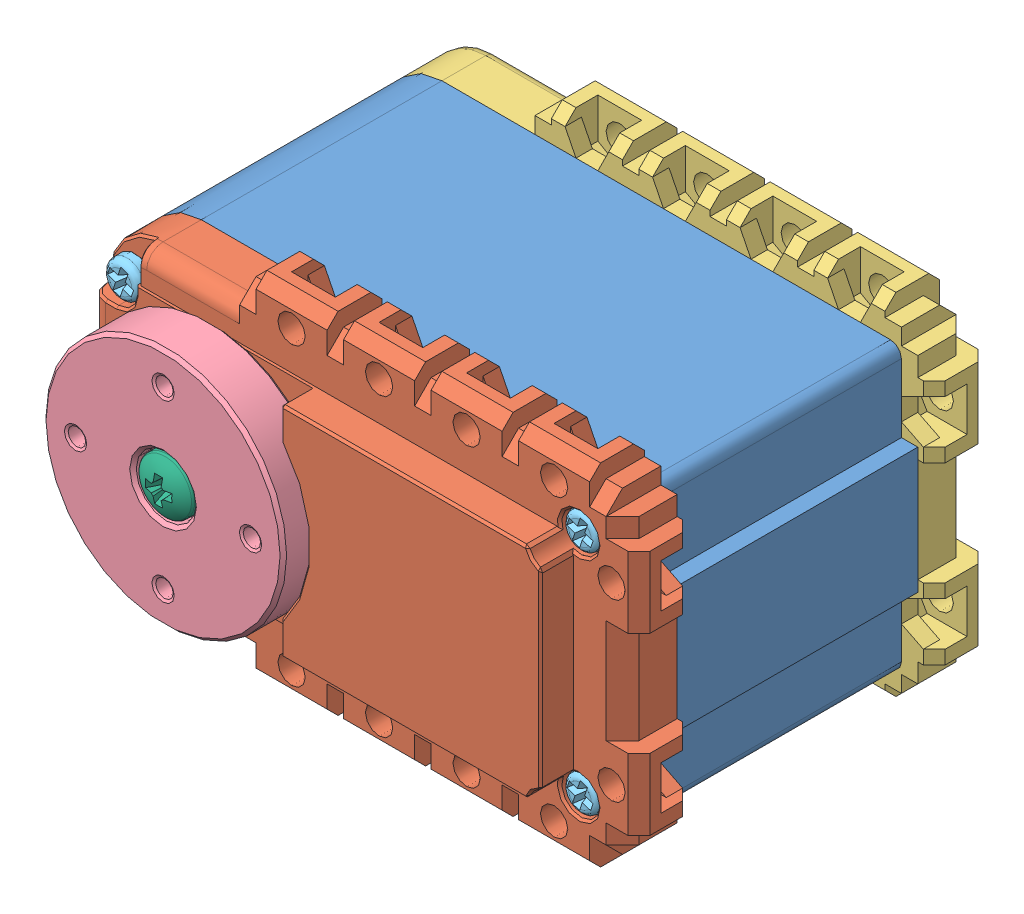
SolidWorks assembly AX-12A, configuration Default. Lengths in mm.
Overall size (50 32 40.55).
9 component instances, 6 part files, 19 mates.
Components (placement in the parent):
- AX-12A-01-1: AX-12A-01 [Default] at origin size (48.5 26 22)
- AX-12A-02-1: AX-12A-02 [Default] at (0 0 13.5) size (50 32 8)
- AX-12A-03-1: AX-12A-03 [Default] at (0 0 -13.5) x (1 0 0) z (0 0 -1) size (50 32 8)
- AX-12A-04-1: AX-12A-04 [Default] at (0 0 21) size (22 22 6.7)
- SetScrew-5: SetScrew [Default] at (33 10.4 14.5) x (0.31498 0.949098 0) z (0 0 -1) size (3.3 3.3 29.44)
- SetScrew-6: SetScrew [Default] at (-9 9.25 14.5) x (0.31498 0.949098 0) z (0 0 -1) size (3.3 3.3 29.44)
- SetScrew-7: SetScrew [Default] at (-9 -9.25 14.5) x (-0.958559 0.284893 0) z (0 0 -1) size (3.3 3.3 29.44)
- SetScrew-8: SetScrew [Default] at (33 -10.4 14.5) x (0.31498 0.949098 0) z (0 0 -1) size (3.3 3.3 29.44)
- pan head cross recess screw_iso-1: pan head cross recess screw_iso [ISO 7045 - M2.5 x 8 - Z --- 8C] at (0 0 21.6) x (0 0 -1) z (1 0 0) size (10.05 5 5)
Mates (geometry in assembly coordinates):
- Coincident1: coincident anti-aligned: plane of AX-12A-01-1 through (0 0 11) normal (0 0 1); plane of AX-12A-02-1 through (0 0 11) normal (0 0 -1)
- Coincident2: coincident aligned: plane of AX-12A-01-1 through (0 0 0) normal (1 0 0); plane of AX-12A-02-1 through (0 0 13.5) normal (1 0 0)
- Coincident3: coincident aligned: plane of AX-12A-01-1 through (0 0 0) normal (0 1 0); plane of AX-12A-02-1 through (0 0 13.5) normal (0 1 0)
- Coincident4: coincident anti-aligned: plane of AX-12A-01-1 through (0 0 -11) normal (0 0 -1); plane of AX-12A-03-1 through (0 0 -11) normal (0 0 1)
- Coincident5: coincident aligned: plane of AX-12A-01-1 through (0 0 0) normal (1 0 0); plane of AX-12A-03-1
- Coincident6: coincident anti-aligned: plane of AX-12A-01-1 through (0 0 0) normal (0 1 0); plane of AX-12A-03-1 through (0 0 -13.5) normal (0 -1 0)
- Concentric1: concentric anti-aligned: cylinder of AX-12A-02-1 through (0 0 13.75) axis (0 0 1) radius 4.75; cylinder of AX-12A-04-1 through (0 0 21) axis (0 0 -1) radius 4.5
- Distance1: distance = 5 mm aligned: plane of AX-12A-02-1 through (0 0 16) normal (0 0 1); plane of AX-12A-04-1 through (0 2.75 21) normal (0 0 1)
- Coincident7: coincident aligned: plane of AX-12A-04-1 through (0 0 21) normal (1 0 0); plane of assembly through (0 0 0) normal (1 0 0)
- Concentric2: concentric aligned: cylinder of AX-12A-02-1 through (33 10.4 11) axis (0 0 1) radius 1; cylinder of SetScrew-5 through (33 10.4 14.5) axis (0 0 1) radius 0.85
- Coincident8: coincident anti-aligned: plane of AX-12A-02-1 through (0 0 14.5) normal (0 0 1); plane of SetScrew-5 through (33.8067 10.1323 14.5) normal (0 0 -1)
- Concentric3: concentric aligned: cylinder of AX-12A-02-1 through (-9 9.25 11) axis (0 0 1) radius 1; cylinder of SetScrew-6 through (-9 9.25 14.5) axis (0 0 1) radius 0.85
- Coincident9: coincident anti-aligned: plane of AX-12A-02-1 through (0 0 14.5) normal (0 0 1); plane of SetScrew-6 through (-8.1933 8.9823 14.5) normal (0 0 -1)
- Concentric4: concentric aligned: cylinder of AX-12A-02-1 through (-9 -9.25 11) axis (0 0 1) radius 1; cylinder of SetScrew-7 through (-9 -9.25 14.5) axis (0 0 1) radius 0.85
- Coincident10: coincident anti-aligned: plane of AX-12A-02-1 through (0 0 14.5) normal (0 0 1); plane of SetScrew-7 through (-8.7578 -8.4352 14.5) normal (0 0 -1)
- Concentric5: concentric aligned: cylinder of AX-12A-02-1 through (33 -10.4 11) axis (0 0 1) radius 1; cylinder of SetScrew-8 through (33 -10.4 14.5) axis (0 0 1) radius 0.85
- Coincident11: coincident anti-aligned: plane of AX-12A-02-1 through (0 0 14.5) normal (0 0 1); plane of SetScrew-8 through (33.8067 -10.6677 14.5) normal (0 0 -1)
- Concentric71: concentric anti-aligned: cylinder of AX-12A-04-1 through (0 0 21) axis (0 0 -1) radius 2.75; cylinder of pan head cross recess screw_iso-1 through (0 0 47) axis (0 0 1) radius 2.5
- Coincident131: coincident anti-aligned: plane of AX-12A-04-1 through (0 2.75 19.5) normal (0 0 1); plane of pan head cross recess screw_iso-1 through (0 1.25 19.5) normal (0 0 -1)
